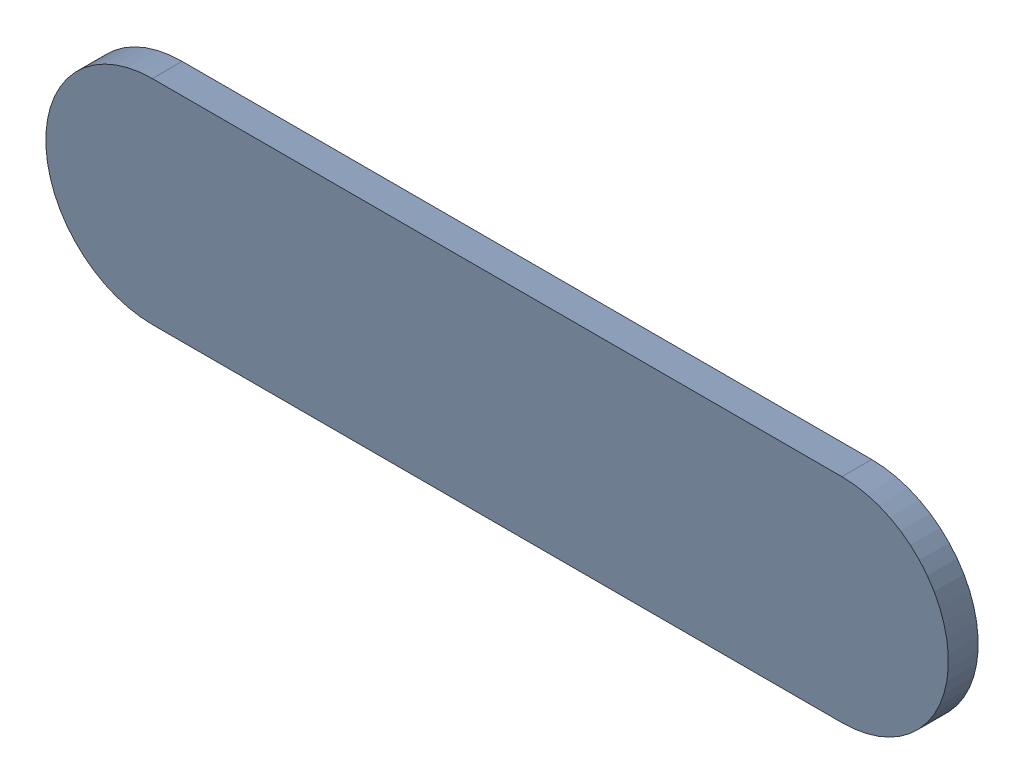
SolidWorks assembly Track (23mm,58.097mm)(23.822mm,58.097mm) on Top Layer, configuration Predeterminado. Lengths in mm.
Overall size (1.08 0.25 0.04).
2 component instances, 1 part files, 0 mates.
Components (placement in the parent):
- Track (23mm,58.097mm)(23.822mm,58.097mm) on Top Layer-1-1: Track (23mm,58.097mm)(23.822mm,58.097mm) on Top Layer-1 [Predeterminado] at (-68.317 -44.187 -0.0457) size (1.08 0.25 0.04)
  - Track (23mm,58.097mm)(23.822mm,58.097mm) on Top Layer-Part-1-1: Track (23mm,58.097mm)(23.822mm,58.097mm) on Top Layer-Part-1 [Predeterminado] at origin size (1.08 0.25 0.04)
